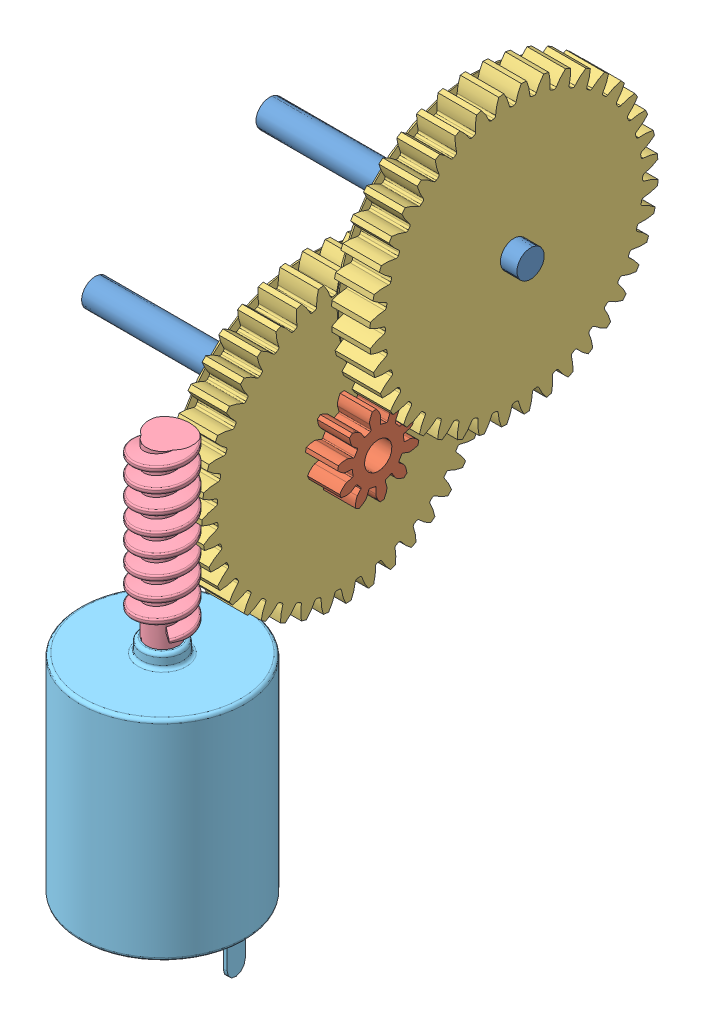
SolidWorks assembly Gearbox Assm, configuration Default. Lengths in mm.
Overall size (46.43 92.76 77.67).
12 component instances, 9 part files, 0 mates.
Components (placement in the parent):
- Shaft - NOPRINT-1: Shaft - NOPRINT [Default] at (-107.6001 5.9531 -21.062) x (0 0.942739 -0.333533) z (1 0 0) size (4 4 38)
- 10T - NOPRINT-1: 10T - NOPRINT [Default] at (-72.1379 5.9531 -21.062) x (0 -0.21694 -0.976185) z (1 0 0) size (12 11.58 6)
- Shaft - NOPRINT-2: Shaft - NOPRINT [Default] at (-62.8128 22.6416 -39.6763) x (0 0.14972 -0.988728) z (-1 0 0) size (4 4 38)
- 40T - NOPRINT-1: 40T - NOPRINT [Default] at (-76.674 5.9531 -21.062) x (0 0.173701 -0.984799) z (1 0 0) size (42 42 5.85)
- 40T - NOPRINT-2: 40T - NOPRINT [Default] at (-70.824 22.6416 -39.6763) x (0 0.068717 0.997636) z (1 0 0) size (42 42 5.85)
- Worm Gear - NOPRINT-1: Worm Gear - NOPRINT [Default] at (-74.4032 -9.226 2.3599) x (-0.817926 0 -0.575323) z (0 1 0) size (9.28 9.15 25.25)
- 97_BottomPlate_AC_N1-1: 97_BottomPlate_AC_N1 [Default] at (-54.9032 -26.9769 -25.7401) x (0 0 1) z (0 1 0) (suppressed, hidden)
- DCMotor1 - NOPRINT-1: DCMotor1 - NOPRINT [Default] at (-74.4032 -41.726 2.3599) x (0.994033 0 -0.109084) z (0 1 0) size (24 24 48.5)
- 97_TopPlate_AC_N1-1: 97_TopPlate_AC_N1 [Default] at (-92.9032 45.8862 -25.7401) x (0 0 -1) z (0 1 0) (suppressed, hidden)
- 97_BackPlate_AC_N1-1: 97_BackPlate_AC_N1 [Default] at (-96.2032 11.77 -56.0661) x (0 0 -1) z (1 0 0) (suppressed, hidden)
- 97_SidePlate_AC_N2-1: 97_SidePlate_AC_N2 [Default] at (-54.9032 -23.6861 -68.4481) (suppressed, hidden)
- 97_SidePlate_AC_N2-2: 97_SidePlate_AC_N2 [Default] at (-54.9032 -23.6861 20.7599) (suppressed, hidden)
